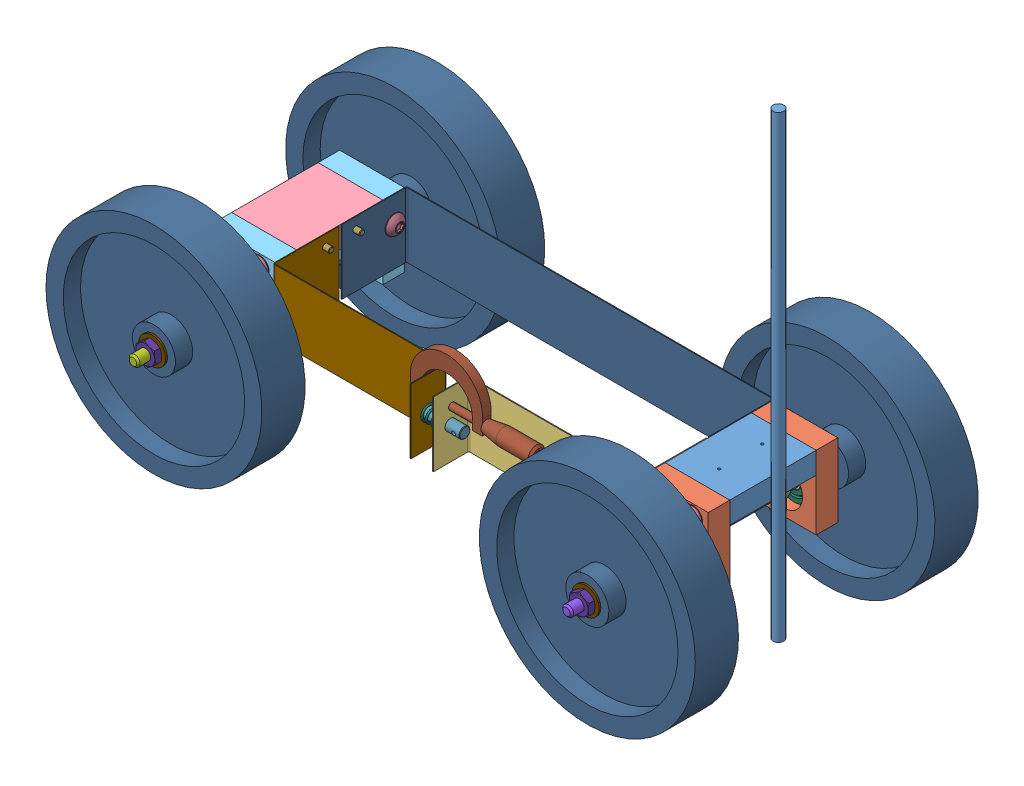
SolidWorks assembly Gravity car assembly (Split frame), configuration Default. Lengths in mm.
Overall size (406.2 298.79 191.04).
66 component instances, 33 part files, 33 mates.
Components (placement in the parent):
- Front Axle Assembly-2: Front Axle Assembly [Default] at (87.1913 142.031 189.0581) size (164.58 298.79 190.98)
  - Connection Front Suspention-1: Connection Front Suspention [Default] at (-53.6547 15.4423 62.2716) size (38.1 12.7 50.8)
  - suspension front-1: suspension front [Default] at (-72.7047 -21.3877 74.9716) size (38.1 43.18 12.7)
  - suspension front-2: suspension front [Default] at (-72.7047 -21.3877 11.4716) size (38.1 43.18 12.7)
  - Slide Wing Nut-1: Slide Wing Nut [Default] at (-53.6547 8.2033 36.8716) x (0 0 1) z (0 -1 0) size (50.8 6.48 7.05)
  - muffle bearing-1: muffle bearing [Default] at (-53.6547 -6.1477 -1.2284) size (8 8 7)
  - muffle bearing-2: muffle bearing [Default] at (-53.6547 -6.1477 67.9716) size (8 8 7)
  - Threaded Axle Front Left-1: Threaded Axle Front Left [Default] at (-53.6547 -6.1477 83.7836) x (0.967821 0.251639 0) z (0 0 1) size (6.35 6.35 135.47)
  - Adapter One-Way-Bearing-1: Adapter One-Way-Bearing [Default] at (-53.6547 -6.1477 74.9716) x (-0.990269 0.139163 0) z (0 0 -1) size (45 45 20.32)
  - Muffle One-Way-Bearing-1: Muffle One-Way-Bearing [Default] at (-53.6547 -6.1477 84.2916) size (15 15 11)
  - Threaded Axle Front Right-1: Threaded Axle Front Right [Default] at (-53.6547 -6.1477 139.2916) x (0.848775 -0.528754 0) z (0 0 1) size (6.35 6.35 55)
  - muffle wheel right-1: muffle wheel right [Default] at (-53.6547 -6.1477 95.2916) x (0.552032 0.833823 0) z (0 0 1) size (7.94 7.94 31.75)
  - Wheel-1: Wheel [Default] at (-53.6547 -6.1477 114.3416) x (0.992874 0.119172 0) z (0 0 1) size (127 127 25.4)
  - muffle wheel left-1: muffle wheel left [Default] at (-53.6547 -6.1477 -39.3284) size (7.94 7.94 38.1)
  - Wheel-2: Wheel [Default] at (-53.6547 -6.1477 -26.6284) x (-0.36486 0.931062 0) z (0 0 1) size (127 127 25.4)
  - Wingnut-1: Wingnut [Default] at (-63.224 -102.9399 -69.9379) x (0 -1 0) z (0 0 1) size (25.24 12.25 6.43)
  - Button Head Hex Drive Screw 1-4-28-1: Button Head Hex Drive Screw 1-4-28 [Default] at (7.3275 5.2304 29.6861) size (11.1 11.1 16.71)
  - Button Head Hex Drive Screw 1-4-28-2: Button Head Hex Drive Screw 1-4-28 [Default] at (-21.1014 44.8149 44.057) x (0.919454 0.393198 0) z (0 0 -1) size (11.1 11.1 16.71)
  - Button Head Hex Drive Screw 1-4-28-3: Button Head Hex Drive Screw 1-4-28 [Default] at (-19.8729 61.5855 44.057) x (0.622111 0.782929 0) z (0 0 -1) size (11.1 11.1 16.71)
  - Button Head Hex Drive Screw 1-4-28-4: Button Head Hex Drive Screw 1-4-28 [Default] at (-12.9925 5.2304 29.6861) size (11.1 11.1 16.71)
  - Button Head Hex Drive Screw 1-64-1: Button Head Hex Drive Screw 1-64 [Default] at (-66.0699 34.9913 37.8914) x (-0.998887 0 -0.047164) z (0 -1 0) size (3.28 3.28 7.41)
  - Button Head Hex Drive Screw 1-64-2: Button Head Hex Drive Screw 1-64 [Default] at (-37.2671 34.9913 19.4802) x (0.551582 0 -0.83412) z (0 -1 0) size (3.28 3.28 7.41)
  - 608 Ball Bearing-1: 608 Ball Bearing [Default] at (-39.5024 -7.5493 -10.4793) size (22 22 7)
  - 608 Ball Bearing-2: 608 Ball Bearing [Default] at (-39.5024 -7.5493 58.7207) size (22 22 7)
  - One-Way-Bearing-1: One-Way-Bearing [Default] at (-39.7809 -11.9333 83.3481) x (0.996606 0.082318 0) z (0 0 1) size (35 35 11)
  - Stainless Steel Thin Hex Nut 1-4-28-1: Stainless Steel Thin Hex Nut 1-4-28 [Default] at (-18.3908 36.8704 -65.2317) x (0.923728 0.383049 0) z (0.383049 -0.923728 0) size (11.11 4.67 12.83)
  - Stainless Steel Thin Hex Nut 1-4-28-3: Stainless Steel Thin Hex Nut 1-4-28 [Default] at (-4.6024 -32.3769 152.9449) x (1 0 0) z (0 1 0) size (11.11 4.67 12.83)
  - Stainless Steel Thin Hex Nut 1-4-28-4: Stainless Steel Thin Hex Nut 1-4-28 [Default] at (-4.6024 -32.3769 88.8139) x (1 0 0) z (0 1 0) size (11.11 4.67 12.83)
  - 316 Stainless Steel Washer-1: 316 Stainless Steel Washer [Default] at (-18.7651 29.0423 -40.1203) x (1 0 0) z (0 -1 0) size (15.87 1.09 15.87)
  - 316 Stainless Steel Washer-2: 316 Stainless Steel Washer [Default] at (-18.7651 -41.3376 127.8334) x (1 0 0) z (0 1 0) size (15.87 1.09 15.87)
  - Wooden Rod-1: Wooden Rod [Default] at (-31.4297 -59.6477 36.8716) x (-0.156429 0 -0.987689) z (0 1 0) size (6.35 6.35 270)
  - Compression Spring Break-1: Compression Spring Break [Default] at (-95.3507 -1.2922 45.8268) x (-0.627574 0.778557 0) z (0.778557 0.627574 0) size (7.88 17.75 8)
- Frame 1 Front-1: Frame 1 Front [Default] at (52.12 125.7234 264.7663) x (0 1 0) z (0 0 -1) size (38.1 102.07 59.31)
- rear axle assembly-2: rear axle assembly [Default] at (-186.4327 107.1435 309.604) x (-1 0 0) z (0 0 -1) size (137.94 137.94 191.03)
  - Connection Rear Suspention-1: Connection Rear Suspention [Default] at (34.964 50.3299 109.0743) size (38.1 12.7 50.8)
  - suspension rear-1: suspension rear [Default] at (15.914 13.4999 121.7743) size (38.1 43.18 12.7)
  - suspension rear-3: suspension rear [Default] at (15.914 13.4999 58.2743) size (38.1 43.18 12.7)
  - threaded axle rear left-1: threaded axle rear left [Default] at (34.964 28.7399 172.2163) x (0.913913 -0.405911 0) z (0 0 1) size (6.35 6.35 63.14)
  - threaded axle rear right-1: threaded axle rear right [Default] at (34.964 28.7399 58.2743) x (0.899499 -0.436922 0) z (0 0 1) size (6.35 6.35 77.09)
  - muffle rear wheels-1: muffle rear wheels [Default] at (34.964 28.7399 25.2543) x (-0.147836 -0.989012 0) z (0 0 -1) size (25.4 25.4 31.75)
  - muffle rear wheels-2: muffle rear wheels [Default] at (34.964 28.7399 128.1243) x (0.995012 -0.099759 0) z (0 0 1) size (25.4 25.4 31.75)
  - Wheel-1: Wheel [Default] at (34.964 28.7399 147.1743) x (-0.032877 -0.999459 0) z (0 0 1) size (127 127 25.4)
  - Wheel-2: Wheel [Default] at (34.964 28.7399 6.2043) x (-0.090252 -0.995919 0) z (0 0 1) size (127 127 25.4)
  - Button Head Hex Drive Screw 1-4-28-1: Button Head Hex Drive Screw 1-4-28 [Default] at (95.9461 40.1179 76.4889) size (11.1 11.1 16.71)
  - Button Head Hex Drive Screw 1-4-28-2: Button Head Hex Drive Screw 1-4-28 [Default] at (75.6261 40.1179 76.4889) size (11.1 11.1 16.71)
  - Button Head Hex Drive Screw 1-4-28-3: Button Head Hex Drive Screw 1-4-28 [Default] at (25.1415 2.4981 90.8598) x (-0.559698 -0.828696 0) z (0 0 -1) size (11.1 11.1 16.71)
  - Button Head Hex Drive Screw 1-4-28-4: Button Head Hex Drive Screw 1-4-28 [Default] at (27.966 -1.4116 90.8598) x (-0.136827 -0.990595 0) z (0 0 -1) size (11.1 11.1 16.71)
  - 316 Stainless Steel Washer-1: 316 Stainless Steel Washer [Default] at (69.8536 -6.45 -6.796) x (1 0 0) z (0 1 0) size (15.87 1.09 15.87)
  - Stainless Steel Thin Hex Nut 1-4-28-1: Stainless Steel Thin Hex Nut 1-4-28 [Default] at (79.493 -4.5958 13.2545) x (0.988533 -0.151006 0) z (0.151006 0.988533 0) size (11.11 4.67 12.83)
  - Stainless Steel Thin Hex Nut 1-4-28-2: Stainless Steel Thin Hex Nut 1-4-28 [Default] at (84.0162 2.5107 50.0655) x (1 0 0) z (0 1 0) size (11.11 4.67 12.83)
  - Stainless Steel Thin Hex Nut 1-4-28-3: Stainless Steel Thin Hex Nut 1-4-28 [Default] at (89.5431 39.474 140.1242) x (0.956264 -0.292503 0) z (-0.292503 -0.956264 0) size (11.11 4.67 12.83)
  - Stainless Steel Thin Hex Nut 1-4-28-4: Stainless Steel Thin Hex Nut 1-4-28 [Default] at (84.0162 54.9691 103.3132) x (1 0 0) z (0 -1 0) size (11.11 4.67 12.83)
  - 316 Stainless Steel Washer-2: 316 Stainless Steel Washer [Default] at (69.8536 -6.45 160.6662) x (1 0 0) z (0 1 0) size (15.87 1.09 15.87)
- Frame 1 Rear-1: Frame 1 Rear [Default] at (-239.98 163.8234 264.7663) x (0 -1 0) z (0 0 -1) size (38.1 102.07 59.31)
- Frame 2-1: Frame 2 [Default] at (-93.93 144.7734 187.0931) x (0 -1 0) z (0 0 1) size (38.1 216.83 38.57)
- micrometer-1: micrometer [Default] at (-87.072 154.5295 275.8595) size (79.21 32.22 9.73)
- Dovel Pin-1: Dovel Pin [Default] at (-180.8731 155.7714 214.5027) size (9.53 3.17 3.17)
- Dovel Pin-2: Dovel Pin [Default] at (36.8755 155.7714 214.5027) size (9.53 3.17 3.17)
- Dovel Pin-3: Dovel Pin [Default] at (37.0749 156.6444 196.6684) x (1 0 0) z (0 -0.042895 0.99908) size (9.53 3.17 3.17)
- Dovel Pin-4: Dovel Pin [Default] at (-180.6606 159.7623 196.7804) x (1 0 0) z (0 -0.194828 0.980837) size (9.53 3.17 3.17)
- Button Head Hex Drive Screw-1: Button Head Hex Drive Screw [Default] at (-222.5435 144.9102 278.0185) x (0 -0.37422 0.92734) z (1 0 0) size (11.1 11.1 16.71)
- Button Head Hex Drive Screw-2: Button Head Hex Drive Screw [Default] at (-222.5435 155.4902 174.7001) x (0 0.518952 -0.854804) z (1 0 0) size (11.1 11.1 16.71)
- Button Head Hex Drive Screw-3: Button Head Hex Drive Screw [Default] at (34.6834 149.1415 214.8399) x (0 0.229818 0.973234) z (-1 0 0) size (11.1 11.1 16.71)
- Button Head Hex Drive Screw-4: Button Head Hex Drive Screw [Default] at (35.137 166.9672 248.2355) x (0 0.777919 -0.628364) z (-1 0 0) size (11.1 11.1 16.71)
- Clevis Pin-1: Clevis Pin [Default] at (-74.1199 148.1369 260.5172) x (0 0.193544 -0.981092) z (-1 0 0) size (9.65 9.65 24.77)
- Compression Spring-1: Compression Spring [Default] at (-107.1337 156.2016 259.2559) x (0 0.59115 -0.806562) z (1 0 0) size (9.45 9.58 13.23)
Mates (geometry in assembly coordinates):
- Parallel1: parallel: plane of Front Axle Assembly-2/Connection Front Suspention-1 through (14.4865 151.1234 200.5297) normal (-1 0 0); plane of rear axle assembly-2/Connection Rear Suspention-1 through (-202.3466 151.1234 251.3297) normal (1 0 0)
- Coincident5: coincident: plane of Front Axle Assembly-2/suspension front-2 through (14.4865 120.6434 187.8297) normal (0 0 -1); plane of rear axle assembly-2/suspension rear-1 through (-202.3466 120.6434 187.8297) normal (0 0 -1)
- Coincident8: coincident: plane of Front Axle Assembly-2/Connection Front Suspention-1 through (14.4865 163.8234 200.5297) normal (0 1 0); plane of rear axle assembly-2/Connection Rear Suspention-1 through (-202.3466 163.8234 251.3297) normal (0 1 0)
- Coincident12: coincident: plane of rear axle assembly-2/suspension rear-1 through (-202.3466 120.6434 200.5297) normal (1 0 0); plane of Frame 2-1 through (-202.3466 144.7734 79.1017) normal (-1 0 0)
- Concentric7: concentric: circle of rear axle assembly-2/suspension rear-1; circle of Frame 2-1
- Concentric8: concentric: circle of rear axle assembly-2/Connection Rear Suspention-1; circle of Frame 2-1
- Concentric9: concentric: circle of Front Axle Assembly-2/suspension front-2; circle of Frame 2-1
- Coincident14: coincident: plane of Front Axle Assembly-2/Connection Front Suspention-1 through (14.4865 151.1234 200.5297) normal (-1 0 0); plane of Frame 2-1 through (14.4865 144.7734 79.1017) normal (1 0 0)
- Coincident26: coincident: plane of Front Axle Assembly-2/suspension front-1 through (14.4865 120.6434 251.3297) normal (-1 0 0); plane of Frame 1 Front-1 through (14.4865 125.7234 226.7077) normal (1 0 0)
- Concentric35: concentric: circle of Front Axle Assembly-2/suspension front-1; circle of Frame 1 Front-1
- Coincident27: coincident: plane of Front Axle Assembly-2/Connection Front Suspention-1 through (14.4865 163.8234 200.5297) normal (0 1 0); plane of Frame 1 Front-1 through (14.4865 163.8234 226.7077) normal (0 1 0)
- Coincident28: coincident: plane of rear axle assembly-2/Connection Rear Suspention-1 through (-202.3466 151.1234 251.3297) normal (1 0 0); plane of Frame 1 Rear-1 through (-202.3466 163.8234 226.7077) normal (-1 0 0)
- Concentric36: concentric: circle of rear axle assembly-2/suspension rear-3; circle of Frame 1 Rear-1
- Coincident29: coincident: plane of rear axle assembly-2/Connection Rear Suspention-1 through (-202.3466 163.8234 251.3297) normal (0 1 0); plane of Frame 1 Rear-1 through (-202.3466 163.8234 226.7077) normal (0 1 0)
- Coincident33: coincident: plane of Frame 1 Rear-1 through (-100.788 163.8234 125.9995) normal (-1 0 0); plane of micrometer-1 through (-100.788 154.5295 275.8595) normal (1 0 0)
- Coincident34: coincident: line of Frame 1 Rear-1 through (-100.788 163.8234 266.0109) axis (0 0 1); cylinder of micrometer-1 through (-87.072 157.1228 278.3995) axis (0 0 -1) radius 15.2652
- Distance1: distance = 7.62 mm: plane of micrometer-1 through (-87.072 160.6131 278.3995) normal (0 0 1); line of Frame 1 Rear-1 through (-100.788 163.8234 286.0195) axis (0 -1 0)
- Concentric37: concentric: cylinder of rear axle assembly-2/Connection Rear Suspention-1 through (-202.3466 157.4734 217.0397) axis (1 0 0) radius 1.5875; cylinder of Dovel Pin-4 through (-207.4418 157.4734 217.0397) axis (1 0 0) radius 1.5875
- Concentric38: concentric: cylinder of rear axle assembly-2/Connection Rear Suspention-1 through (-202.3466 157.4734 234.8197) axis (1 0 0) radius 1.5875; cylinder of Dovel Pin-1 through (-207.6543 157.4734 234.8197) axis (1 0 0) radius 1.5875
- Concentric39: concentric: cylinder of Front Axle Assembly-2/Connection Front Suspention-1 through (14.4865 157.4734 217.0397) axis (-1 0 0) radius 1.5875; cylinder of Dovel Pin-3 through (10.2937 157.4734 217.0397) axis (1 0 0) radius 1.5875
- Concentric40: concentric: cylinder of Front Axle Assembly-2/Connection Front Suspention-1 through (14.4865 157.4734 234.8197) axis (-1 0 0) radius 1.5875; cylinder of Dovel Pin-2 through (10.0943 157.4734 234.8197) axis (1 0 0) radius 1.5875
- Concentric41: concentric: cylinder of rear axle assembly-2/suspension rear-3 through (-202.3466 148.5834 257.6797) axis (1 0 0) radius 2.5527; circle of Button Head Hex Drive Screw-1
- Coincident35: coincident: plane of Frame 1 Rear-1 through (-201.8386 163.8234 226.7077) normal (1 0 0); plane of Button Head Hex Drive Screw-1 through (-201.8386 143.4367 255.6028) normal (-1 0 0)
- Concentric42: concentric: circle of rear axle assembly-2/suspension rear-1; circle of Button Head Hex Drive Screw-2
- Coincident36: coincident: plane of Frame 2-1 through (-201.8386 144.7734 79.1017) normal (1 0 0); plane of Button Head Hex Drive Screw-2 through (-201.8386 153.3274 197.0598) normal (-1 0 0)
- Concentric43: concentric: circle of Front Axle Assembly-2/suspension front-2; circle of Button Head Hex Drive Screw-3
- Coincident37: coincident: plane of Frame 2-1 through (13.9785 144.7734 79.1017) normal (-1 0 0); plane of Button Head Hex Drive Screw-3 through (13.9785 153.9847 192.9042) normal (1 0 0)
- Concentric44: concentric: circle of Front Axle Assembly-2/suspension front-1; circle of Button Head Hex Drive Screw-4
- Coincident38: coincident: plane of Frame 1 Front-1 through (13.9785 125.7234 226.7077) normal (-1 0 0); circle of Button Head Hex Drive Screw-4
- Concentric45: concentric: circle of Frame 1 Rear-1; circle of Clevis Pin-1
- Coincident39: coincident: plane of Frame 1 Rear-1 through (-100.788 163.8234 125.9995) normal (-1 0 0); plane of Clevis Pin-1 through (-100.788 144.7734 276.0152) normal (1 0 0)
- Coincident40: coincident: plane of Frame 1 Rear-1 through (-100.28 163.8234 125.9995) normal (1 0 0); plane of Compression Spring-1 through (-100.28 144.815 276.1465) normal (-1 0 0)
- Lock1: lock: unknown of Clevis Pin-1; unknown of Compression Spring-1
